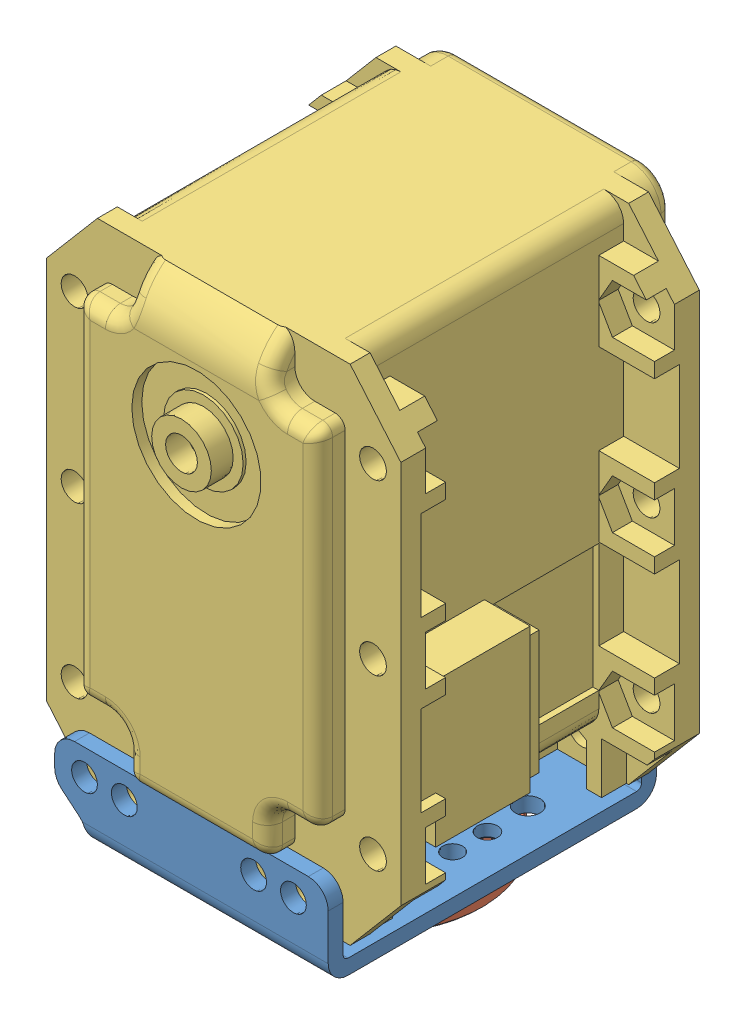
SolidWorks assembly Link6, configuration Default. Lengths in mm.
Overall size (35.6 56.91 41.85).
3 component instances, 3 part files, 6 mates.
Components (placement in the parent):
- FR07-S101-1: FR07-S101 [Default] at (-3.5315 18.2682 31.0125) size (27.5 8.61 33.02)
- HN07-N101-1: HN07-N101 [Default] at (-3.5315 16.2682 31.0125) x (0 0 1) z (-1 0 0) size (22 5.85 22)
- MX-28T_R-1: MX-28T_R [Default] at (-3.5315 60.0682 31.0125) x (-1 0 0) z (0 0 -1) size (35.6 50.71 41.85)
Mates (geometry in assembly coordinates):
- Concentric1: concentric: circle of MX-28T_R-1; circle of FR07-S101-1
- Concentric2: concentric: circle of FR07-S101-1; circle of MX-28T_R-1
- Coincident1: coincident anti-aligned: plane of FR07-S101-1 through (8.4685 20.2682 16.0125) normal (0 0 1); plane of MX-28T_R-1 through (-3.5315 60.0682 16.0125) normal (0 0 -1)
- Concentric3: concentric: circle of FR07-S101-1; circle of HN07-N101-1
- Concentric4: concentric: circle of FR07-S101-1; circle of HN07-N101-1
- Coincident2: coincident anti-aligned: plane of FR07-S101-1 through (8.4685 18.2682 45.5125) normal (0 -1 0); plane of HN07-N101-1 through (-3.5315 18.2682 31.0125) normal (0 1 0)
